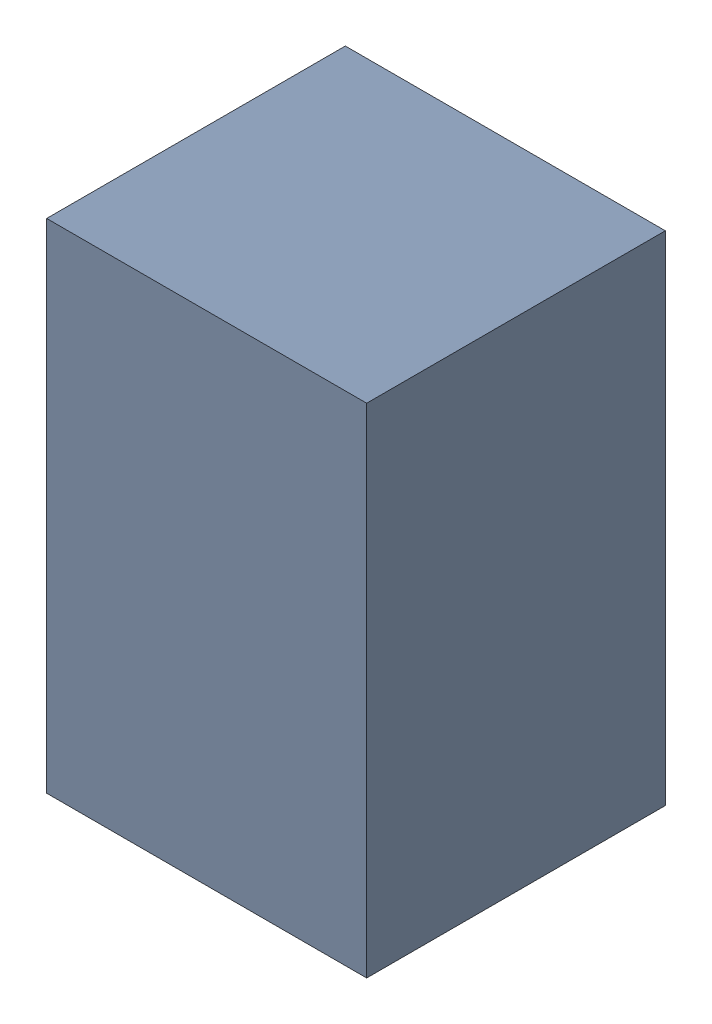
SolidWorks assembly C7, configuration Default. Lengths in mm.
Overall size (1.35 2.1 1.26).
2 component instances, 1 part files, 0 mates.
Components (placement in the parent):
- 407985696-1: 407985696 [Default] at (19.177 43.307 0.0127) size (1.35 2.1 1.26)
  - Extruded_1-1: Extruded_1 [Default] at origin size (1.35 2.1 1.26)
